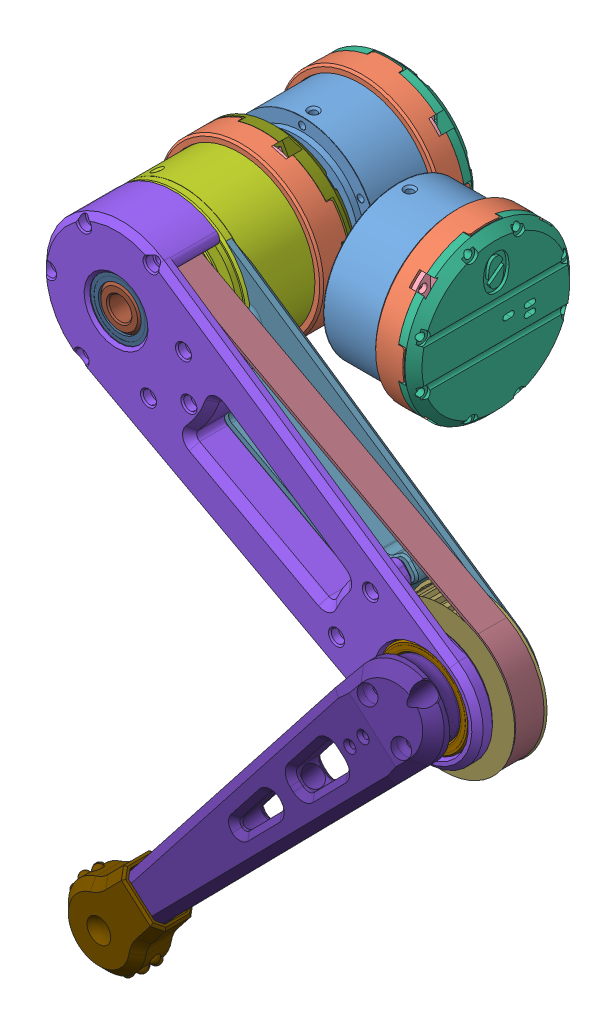
SolidWorks assembly Leg - Three DOF, configuration Default. Lengths in mm.
Overall size (202.76 276.15 115.13).
35 component instances, 19 part files, 21 mates.
Components (placement in the parent):
- J2 010-1: J2 010 [Default] at (166.4647 190.7094 671.5737) size (144 58 38.39)
  - Servo (wo front plate) 010-1: Servo (wo front plate) 010 [Default] at (17.7375 29.5761 27.1952) size (52.8 52.8 26)
  - J2 Front Plate 011-1: J2 Front Plate 011 [Default] at (17.7375 29.5761 49.1952) size (144 57.5 6) (hidden)
  - Back Plate 012-1: Back Plate 012 [Default] at (17.7375 29.5761 28.9452) x (1 0 0) z (0 1 0) size (58 10.25 57.37)
  - Magnet Holder 011-1: Magnet Holder 011 [Default] at (17.7375 29.5761 33.9952) x (0.637878 -0.770138 0) z (0 0 -1) size (8.5 8.5 8.5)
  - Dagor Controller 2.5-1: Dagor Controller 2.5 [Default] at (-33.0562 -36.3481 -63.7332) size (44 44 7.5)
    - Dagor Controller Board 2.5-1: Dagor Controller Board 2.5 [Predeterminado] at (50.7937 65.9242 86.1284) size (44 44 7.5)
    - ESP32-WROOM-32U-1: ESP32-WROOM-32U [Default] at (44.7937 81.3242 85.1634) x (1 0 0) z (0 0 -1) size (18.07 19.38 3.04)
  - J2 Back Plate B 014-1: J2 Back Plate B 014 [Default] at (17.7375 29.5761 20.6952) x (-1 0 0) z (0 0 -1) size (58 58 5.89)
- J3 010-1: J3 010 [Default] at (184.7408 187.9987 711.8116) x (0.876962 0.48056 0) z (0 0 1) size (133.1 179.04 61.49)
  - Servo 010-1: Servo 010 [Default] at (15.0435 28.5731 29.2983) size (52.8 52.8 26)
  - Femur 011-1: Femur 011 [Default] at (15.0435 28.5731 74.4483) x (0.866025 0.5 0) z (0 0 1) size (53 172 20.25)
  - 6705 Bearing-1: 6705 Bearing [Predeterminado] at (77.7935 -80.1131 71.4983) x (0.989844 0.142156 0) z (0.142156 -0.989844 0) size (32 4.1 32)
  - Bearing 15x24x5mm-1: Bearing 15x24x5mm [Predeterminado] at (15.0435 28.5731 70.6483) x (1 0 0) z (0 -1 0) size (24 5.1 24)
  - Pulley A 36T 011-1: Pulley A 36T 011 [Predeterminado] at (15.0435 28.5731 66.0983) x (-1 0 0) z (0 0 -1) size (36.31 36.31 18.05)
  - Pulley B 30T 011-2: Pulley B 30T 011 [Predeterminado] at (77.7935 -80.1131 55.8983) x (0.364752 0.931105 0) z (0 0 1) size (50.61 50.61 20.55)
  - Belt 380mm 010-1: Belt 380mm 010 [Default] at (77.7935 -80.1131 65.9983) x (-0.5 0.866025 0) z (-0.866025 -0.5 0) size (168.7 10 50)
  - Femur B 011-1: Femur B 011 [Default] at (15.0435 28.5731 49.7229) x (-0.866025 -0.5 0) z (0 0 -1) size (52.55 140.48 13)
  - 6705 Bearing-2: 6705 Bearing [Predeterminado] at (77.7935 -80.1131 52.4229) x (0.58942 -0.807827 0) z (-0.807827 -0.58942 0) size (32 4.1 32)
  - Back Plate 012-1: Back Plate 012 [Default] at (15.0435 28.5731 31.0483) x (1 0 0) z (0 1 0) size (58 10.25 57.37)
  - Pulley B Plate 010-1: Pulley B Plate 010 [Default] at (77.7935 -80.1131 48.8983) x (-0.364752 -0.931105 0) z (0 0 -1) size (27 27 7.25)
  - Dagor Controller Board 2.5-1: Dagor Controller Board 2.5 [Predeterminado] at (15.0435 28.5731 24.4983) size (44 44 7.5)
  - ESP32-WROOM-32U-1: ESP32-WROOM-32U [Default] at (9.0435 43.9731 23.5333) x (1 0 0) z (0 0 -1) size (18.07 19.38 3.04)
  - Back Plate B 014-1: Back Plate B 014 [Default] at (15.0435 28.5731 22.7073) x (-1 0 0) z (0 0 -1) size (58 58 10.25)
  - Magnet Holder 011-1: Magnet Holder 011 [Default] at (15.0435 28.5731 36.0983) x (0.302113 -0.953272 0) z (0 0 -1) size (8.5 8.5 8.5)
- Low Limb 022-1: Low Limb 022 [Predeterminado] at (291.4618 155.1271 800.0099) x (-0.750946 0.660363 0) z (0 0 -1) size (30 174.81 21)
- Sock 012-1: Sock 012 [Default] at (193.3978 43.6116 794.0099) x (0.750946 -0.660363 0) z (0 0 1) size (30 35.47 15)
- J1 010-1: J1 010 [Default] at (271.1186 190.0326 708.7218) x (0 0 1) z (-1 0 0) size (58 58 38.39)
  - Servo (wo front plate) 010-1: Servo (wo front plate) 010 [Default] at (16.2104 31.3314 26.8086) size (52.8 52.8 26)
  - Magnet Holder 011-1: Magnet Holder 011 [Default] at (16.2104 31.3314 33.2086) x (1 0 0) z (0 0 -1) size (8.5 8.5 8.5)
  - Dagor Controller 2.5-1: Dagor Controller 2.5 [Default] at (-34.5833 -34.5928 -64.1198) size (44 44 7.5)
    - Dagor Controller Board 2.5-1: Dagor Controller Board 2.5 [Predeterminado] at (50.7937 65.9242 86.1284) size (44 44 7.5)
    - ESP32-WROOM-32U-1: ESP32-WROOM-32U [Default] at (44.7937 81.3242 85.1634) x (1 0 0) z (0 0 -1) size (18.07 19.38 3.04)
  - Back Plate 012-1: Back Plate 012 [Default] at (16.2104 31.3314 28.5586) x (1 0 0) z (0 1 0) size (58 10.25 57.37)
  - J2 Back Plate B 014-1: J2 Back Plate B 014 [Default] at (16.2104 31.3314 20.3086) x (-1 0 0) z (0 0 -1) size (58 58 5.89)
Mates (geometry in assembly coordinates):
- Coincident1: coincident aligned: plane of Linear Rail 8000mm-1 through (133.2022 813.2855 706.0361) normal (0 1 0); plane of Linear Rail 8000mm-2 through (235.2022 813.2855 706.0361) normal (0 1 0)
- Concentric1: concentric anti-aligned: cylinder of J2 010-1/Servo (wo front plate) 010-1 through (184.2022 220.2855 721.6689) axis (0 0 1) radius 4; cylinder of J3 010-1/Servo 010-1 through (184.2022 220.2855 766.0099) axis (0 0 -1) radius 26.4
- Coincident3: coincident anti-aligned: plane of J2 010-1/Servo (wo front plate) 010-1 through (184.2022 220.2855 724.7689) normal (0 0 1); plane of J3 010-1/Back Plate B 014-1 through (184.2022 220.2855 724.7689) normal (0 0 -1)
- Concentric2: concentric aligned: cylinder of J2 010-1/J2 Front Plate 011-1 through (221.2022 233.2855 718.7689) axis (0 0 1) radius 2.8; cylinder of Linear Bearing 40x40mm 12mm-2 through (221.2022 233.2855 706.1689) axis (0 0 1) radius 2.5
- Concentric3: concentric aligned: cylinder of J2 010-1/J2 Front Plate 011-1 through (249.2022 207.2855 718.7689) axis (0 0 1) radius 2.8; cylinder of Linear Bearing 40x40mm 12mm-2 through (249.2022 207.2855 706.1689) axis (0 0 1) radius 2.5
- Coincident4: coincident anti-aligned: plane of J2 010-1/J2 Front Plate 011-1 through (184.2022 220.2855 720.7689) normal (0 0 -1); plane of Linear Bearing 40x40mm 12mm-2 through (235.2022 220.2855 720.7689) normal (0 0 1)
- Concentric4: concentric aligned: cylinder of J2 010-1/J2 Front Plate 011-1 through (147.2022 207.2855 718.7689) axis (0 0 1) radius 2.8; cylinder of Linear Bearing 40x40mm 12mm-1 through (147.2022 207.2855 706.1689) axis (0 0 1) radius 2.5
- Concentric5: concentric aligned: cylinder of J2 010-1/J2 Front Plate 011-1 through (119.2022 233.2855 718.7689) axis (0 0 1) radius 2.8; cylinder of Linear Bearing 40x40mm 12mm-1 through (119.2022 233.2855 706.1689) axis (0 0 1) radius 2.5
- Coincident5: coincident anti-aligned: plane of J2 010-1/J2 Front Plate 011-1 through (184.2022 220.2855 720.7689) normal (0 0 -1); plane of Linear Bearing 40x40mm 12mm-1 through (133.2022 220.2855 720.7689) normal (0 0 1)
- Concentric6: concentric anti-aligned: cylinder of Linear Rail 8000mm-1 through (133.2022 13.2855 706.0361) axis (0 1 0) radius 6; cylinder of Linear Bearing 40x40mm 12mm-1 through (133.2022 240.2855 706.0361) axis (0 -1 0) radius 6.25
- Concentric7: concentric anti-aligned: cylinder of Linear Rail 8000mm-2 through (235.2022 13.2855 706.0361) axis (0 1 0) radius 6; cylinder of Linear Bearing 40x40mm 12mm-2 through (235.2022 240.2855 706.0361) axis (0 -1 0) radius 6.25
- Coincident6: coincident aligned: plane of Linear Rail 8000mm-1 through (118.2022 13.2855 683.8361) normal (0 0 -1); plane of Linear Rail 8000mm-2 through (220.2022 13.2855 683.8361) normal (0 0 -1)
- Concentric8: concentric anti-aligned: cylinder of Linear Rail 8000mm-1 through (133.2022 13.2855 706.0361) axis (0 1 0) radius 6; cylinder of Rail Space 010-1 through (133.2022 20.2855 706.0361) axis (0 -1 0) radius 6.5
- Concentric9: concentric anti-aligned: cylinder of Linear Rail 8000mm-2 through (235.2022 13.2855 706.0361) axis (0 1 0) radius 6; cylinder of Rail Space 010-1 through (235.2022 20.2855 706.0361) axis (0 -1 0) radius 6.5
- Coincident7: coincident aligned: plane of Linear Rail 8000mm-2 through (235.2022 13.2855 706.0361) normal (0 -1 0); plane of Rail Space 010-1 through (184.2022 13.2855 697.9448) normal (0 -1 0)
- Concentric10: concentric anti-aligned: cylinder of J3 010-1/6705 Bearing-1 through (291.4618 155.1271 785.3099) axis (0 0 -1) radius 12.5; cylinder of Low Limb 022-1 through (291.4618 155.1271 784.0099) axis (0 0 1) radius 12.5
- Coincident8: coincident anti-aligned: plane of J3 010-1/Pulley B 36T 010-2 through (291.4618 155.1271 784.0099) normal (0 0 1); plane of Low Limb 022-1 through (291.4618 155.1271 784.0099) normal (0 0 -1)
- Distance1: distance = 180 mm anti-aligned: plane of Rail Space 010-1 through (184.2022 20.2855 697.9448) normal (0 1 0); plane of Linear Bearing 40x40mm 12mm-1 through (113.2022 200.2855 720.7689) normal (0 -1 0)
- Width1: width anti-aligned: plane of Low Limb 022-1 through (279.6595 164.3848 788.0099) normal (-0.786818 0.617185 0); plane of Sock 012-1 through (302.1524 144.6052 788.0099) normal (0.712708 -0.701461 0); plane of Low Limb 022-1 through (200.6817 64.3532 801.5099) normal (0.71418 -0.699962 0); plane of Sock 012-1 through (213.0381 53.4873 801.5099) normal (-0.78552 0.618836 0)
- Width2: width anti-aligned: plane of Sock 012-1 through (216.8254 39.7115 788.0099) normal (0 0 1); plane of Low Limb 022-1 through (216.8254 39.7115 800.0099) normal (0 0 -1); plane of Sock 012-1 through (291.4618 155.1271 788.0099) normal (0 0 -1); plane of Low Limb 022-1 through (291.4618 155.1271 800.0099) normal (0 0 1)
- Concentric11: concentric aligned: cylinder of Low Limb 022-1 through (193.3978 43.6116 798.0099) axis (0 0 -1) radius 10.1; cylinder of Sock 012-1 through (193.3978 43.6116 801.5099) axis (0 0 -1) radius 12.25
